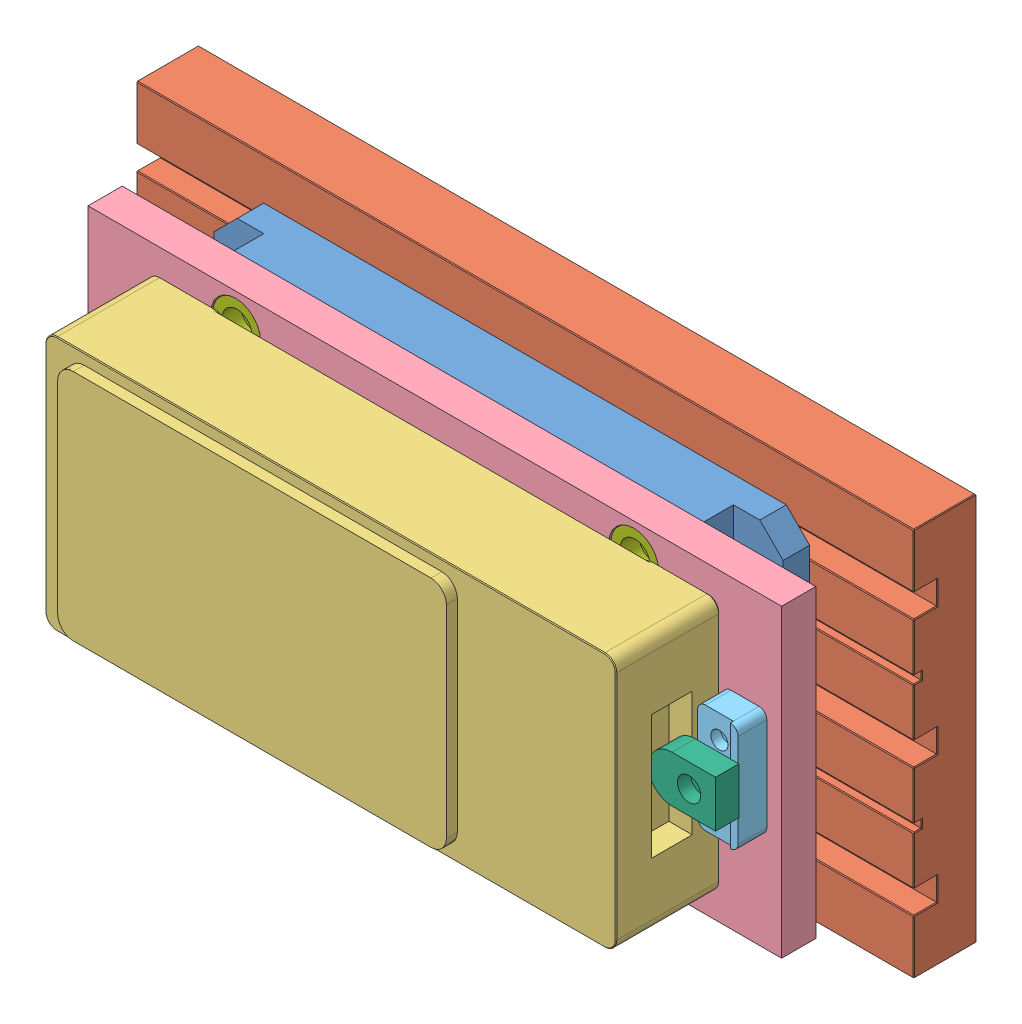
SolidWorks assembly OM2 plateau givrant, configuration Défaut. Lengths in mm.
Overall size (500 250 172).
12 component instances, 7 part files, 16 mates.
Components (placement in the parent):
- Copie de H1000-196-366;Import_e1^OM2 plateau givrant-1: Copie de H1000-196-366;Import_e1^OM2 plateau givrant [Défaut] at (73 0 0) x (-1 0 0) z (0 0 1) size (366 196 36) (virtual)
- Copie de Table^OM2 plateau givrant-1: Copie de Table^OM2 plateau givrant [Défaut] at (0 -24.8767 0) x (-1 0 0) z (0 0 1) size (500 250 40) (virtual)
- Copie de plateau givrant^OM2 plateau givrant-1: Copie de plateau givrant^OM2 plateau givrant [Défaut] at (0 -24.8767 100) x (-1 0 0) z (0 0 1) size (367 165.53 74) (virtual)
- Copie de plaque bridage gel^OM2 plateau givrant-1: Copie de plaque bridage gel^OM2 plateau givrant [Défaut] at (0 -24.8767 98) size (446 196 22) (virtual)
- Copie de porte bride pg^OM2 plateau givrant-1: Copie de porte bride pg^OM2 plateau givrant [Défaut] at (0 -24.8767 98) size (28 70 18.5) (virtual)
- Copie de bride pg^OM2 plateau givrant-1: Copie de bride pg^OM2 plateau givrant [Défaut] at (4.8596 -20.8877 116.5) size (43 30 15) (virtual)
- Copie de bride pg^OM2 plateau givrant-2: Copie de bride pg^OM2 plateau givrant [Défaut] at (-4.8596 -28.8658 116.5) x (-1 0 0) z (0 0 1) size (43 30 15) (virtual)
- Copie de porte bride pg^OM2 plateau givrant-2: Copie de porte bride pg^OM2 plateau givrant [Défaut] at (0 -24.8767 98) x (-1 0 0) z (0 0 1) size (28 70 18.5) (virtual)
- Copie de H_1092_26_2^OM2 plateau givrant-1: Copie de H_1092_26_2^OM2 plateau givrant [Défaut] at (-128 -102.8767 80) x (-0.149502 0.988761 0) z (0 0 1) size (31 31 32) (virtual)
- Copie de H_1092_26_2^OM2 plateau givrant-2: Copie de H_1092_26_2^OM2 plateau givrant [Défaut] at (128 -102.8767 80) x (-0.149502 0.988761 0) z (0 0 1) size (31 31 32) (virtual)
- Copie de H_1092_26_2^OM2 plateau givrant-3: Copie de H_1092_26_2^OM2 plateau givrant [Défaut] at (128 53.1233 80) x (-0.149502 0.988761 0) z (0 0 1) size (31 31 32) (virtual)
- Copie de H_1092_26_2^OM2 plateau givrant-4: Copie de H_1092_26_2^OM2 plateau givrant [Défaut] at (-128 53.1233 80) x (-0.149502 0.988761 0) z (0 0 1) size (31 31 32) (virtual)
Mates (geometry in assembly coordinates):
- Coïncidente1: coincident anti-aligned: plane of Copie de H1000-196-366;Import_e1^OM2 Copie de plateau givrant^OM2 Copie de plateau givrant^OM2 plateau givrant-1 through (183 73.1233 40) normal (0 0 -1); plane of Copie de Table^OM2 plateau givrant-1 through (0 -24.8767 40) normal (0 0 1)
- Symétrique1: symmetric aligned: plane of Copie de H1000-196-366;Import_e1^OM2 Copie de plateau givrant^OM2 Copie de plateau givrant^OM2 Copie de plateau givrant^OM2 plateau givrant-1 through (151 60.1233 57) normal (1 0 0); plane of Copie de Table^OM2 plateau givrant-1 through (-151 60.1233 57) normal (-1 0 0); plane of Copie de H1000-196-366;Import_e1^OM2 plateau givrant-1 through (0 -24.8767 0) normal (-1 0 0)
- Symétrique2: symmetric aligned: plane of Copie de H1000-196-366;Import_e1^OM2 Copie de plateau givrant^OM2 Copie de plateau givrant^OM2 Copie de plateau givrant^OM2 plateau givrant-1 through (-183 -122.8767 76) normal (0 -1 0); plane of Copie de Table^OM2 plateau givrant-1 through (183 73.1233 76) normal (0 1 0); plane of Copie de H1000-196-366;Import_e1^OM2 plateau givrant-1 through (0 -24.8767 0) normal (0 -1 0)
- Coïncidente3: coincident aligned: plane of Copie de Table^OM2 Copie de plateau givrant^OM2 Copie de plateau givrant^OM2 plateau givrant-1 through (0 -24.8767 0) normal (0 -1 0); plane of plateau givrant-1 through (0 -24.8767 100) normal (0 -1 0)
- Coïncidente4: coincident aligned: plane of Copie de Table^OM2 Copie de plateau givrant^OM2 Copie de plateau givrant^OM2 plateau givrant-1 through (0 -24.8767 0) normal (-1 0 0); plane of plateau givrant-1 through (0 -24.8767 100) normal (-1 0 0)
- Distance1: distance = 22 mm anti-aligned: plane of Copie de H1000-196-366;Import_e1^OM2 Copie de plateau givrant^OM2 Copie de plateau givrant^OM2 plateau givrant-1 through (183 73.1233 76) normal (0 0 1); plane of plateau givrant-1 through (-176 -99.3767 98) normal (0 0 -1)
- Coïncidente10: coincident anti-aligned: plane of Copie de plateau givrant^OM2 Copie de plateau givrant^OM2 plateau givrant-1 through (176 49.6233 98) normal (0 0 -1); plane of Copie de plaque bridage gel^OM2 plateau givrant-1 through (0 -24.8767 98) normal (0 0 1)
- Coïncidente11: coincident anti-aligned: plane of Copie de plateau givrant^OM2 Copie de plateau givrant^OM2 plateau givrant-1 through (0 -24.8767 100) normal (0 -1 0); plane of Copie de plaque bridage gel^OM2 plateau givrant-1 through (0 -24.8767 98) normal (0 1 0)
- Coïncidente12: coincident anti-aligned: plane of Copie de plateau givrant^OM2 Copie de plateau givrant^OM2 plateau givrant-1 through (0 -24.8767 100) normal (-1 0 0); plane of Copie de plaque bridage gel^OM2 plateau givrant-1 through (0 -24.8767 98) normal (1 0 0)
- Coïncidente16: coincident aligned: plane of Copie de plaque bridage gel^OM2 plateau givrant-1 through (0 -24.8767 98) normal (0 0 1); plane of Copie de porte bride pg^OM2 plateau givrant-1 through (0 -24.8767 98) normal (0 0 1)
- Coïncidente17: coincident aligned: plane of Copie de plaque bridage gel^OM2 plateau givrant-1 through (0 -24.8767 98) normal (0 1 0); plane of Copie de porte bride pg^OM2 plateau givrant-1 through (0 -24.8767 98) normal (0 1 0)
- Coïncidente18: coincident aligned: plane of Copie de plaque bridage gel^OM2 plateau givrant-1 through (0 -24.8767 98) normal (1 0 0); plane of Copie de porte bride pg^OM2 plateau givrant-1 through (0 -24.8767 98) normal (1 0 0)
- Coïncidente25: coincident anti-aligned: plane of Copie de porte bride pg^OM2 plateau givrant-1 through (0 -24.8767 116.5) normal (0 0 1); plane of bride pg-1 through (186 -24.8767 116.5) normal (0 0 -1)
- Coaxiale2: concentric aligned: cylinder of Copie de porte bride pg^OM2 plateau givrant-1 through (197 -24.8767 114.5) axis (0 0 1) radius 3.4; cylinder of bride pg-1 through (197 -24.8767 131.5) axis (0 0 1) radius 7.5
- Coaxiale3: concentric anti-aligned: cylinder of Copie de plaque bridage gel^OM2 plateau givrant-1 through (-128 -102.8767 98) axis (0 0 1) radius 13; cylinder of H_1092_26_2-1 through (-128 -102.8767 84.95) axis (0 0 -1) radius 13
- Coïncidente27: coincident anti-aligned: plane of Copie de plaque bridage gel^OM2 plateau givrant-1 through (-115 -102.8767 91.7) normal (0 0 1); plane of H_1092_26_2-1 through (-128 -102.8767 91.7) normal (0 0 -1)
